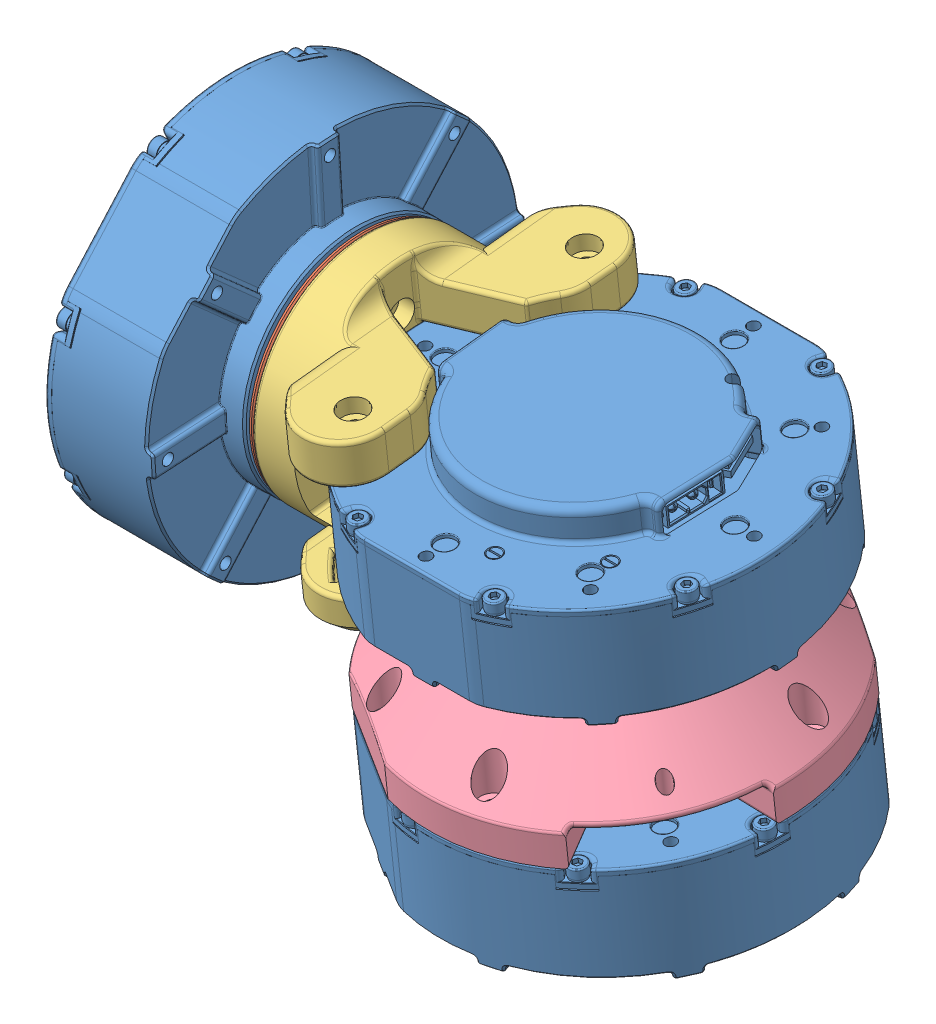
SolidWorks assembly 3自由度单腿-装配体, configuration 默认. Lengths in mm.
Overall size (172.45 137.35 144.34).
11 component instances, 4 part files, 31 mates.
Components (placement in the parent):
- 宇树电机-可转动-1: 宇树电机-可转动 [默认] at (-12.2435 -5.4245 99.9566) size (42.3 98.68 99.96) (flexible)
  - GO-M8010-6电机3D模型-定子-1: GO-M8010-6电机3D模型-定子 [默认] at origin size (42 98.68 99.96)
  - GO-M8010-6电机3D模型-转子-1: GO-M8010-6电机3D模型-转子 [默认] at (105.0963 -198.9147 5.3522) x (1 0 0) z (0 0.306782 -0.95178) size (8.3 59.93 59.79)
- 髋关节连接件 A-1: 髋关节连接件 A [默认] at (101.5018 -193.4249 100.3215) x (0 0.108512 -0.994095) z (0 -0.994095 -0.108512) size (82.01 37.78 59)
- 髋关节连接件 B-1: 髋关节连接件 B [默认] at (160.7523 -214.5992 98.0105) x (0.853082 -0.056619 0.518696) z (0.521777 0.09257 -0.848045) size (93.72 27.46 99.11)
- 宇树电机-可转动-2: 宇树电机-可转动 [默认] at (20.0022 -88.0011 -13.5455) x (0 -0.994095 -0.108512) z (0.664398 0.0811 -0.742965) size (42.3 98.68 99.96) (flexible)
  - GO-M8010-6电机3D模型-定子-1: GO-M8010-6电机3D模型-定子 [默认] at origin size (42 98.68 99.96)
  - GO-M8010-6电机3D模型-转子-1: GO-M8010-6电机3D模型-转子 [默认] at (105.0963 -180.1325 9.4248) x (1 0 0) z (0 -0.999679 -0.025325) size (8.3 59.93 59.79)
- 宇树电机-可转动-3: 宇树电机-可转动 [默认] at (215.7919 -182.3677 282.3599) x (0 -0.994095 -0.108512) z (-0.956751 -0.031567 0.28919) size (42.3 98.68 99.96) (flexible)
  - GO-M8010-6电机3D模型-定子-1: GO-M8010-6电机3D模型-定子 [默认] at origin size (42 98.68 99.96)
  - GO-M8010-6电机3D模型-转子-1: GO-M8010-6电机3D模型-转子 [默认] at (105.0963 -181.6014 10.516) x (1 0 0) z (0 -0.984204 -0.177039) size (8.3 59.93 59.79)
Mates (geometry in assembly coordinates):
- 重合1: coincident anti-aligned: plane of 宇树电机-可转动-1/GO-M8010-6电机3D模型-转子-1 through (101.5018 -165.4622 154.8842) normal (1 0 0); plane of 髋关节连接件 A-1 through (101.5018 -193.4249 100.3215) normal (-1 0 0)
- 同心1: concentric anti-aligned: cylinder of 宇树电机-可转动-1/GO-M8010-6电机3D模型-转子-1 through (97.3518 -203.6201 114.2363) axis (1 0 0) radius 1.65; cylinder of 髋关节连接件 A-1 through (112.5018 -203.6201 114.2363) axis (-1 0 0) radius 2
- 同心2: concentric anti-aligned: cylinder of 宇树电机-可转动-1/GO-M8010-6电机3D模型-转子-1 through (97.3518 -186.4719 116.1081) axis (1 0 0) radius 1.65; cylinder of 髋关节连接件 A-1 through (112.5018 -186.4719 116.1081) axis (-1 0 0) radius 2
- 重合5: coincident anti-aligned: plane of 髋关节连接件 A-1 through (160.7518 -180.5017 101.7321) normal (0 -0.994095 -0.108512); plane of 宇树电机-可转动-2/GO-M8010-6电机3D模型-定子-1 through (75.6761 -181.0443 106.7031) normal (0 0.994095 0.108512)
- 同心6: concentric anti-aligned: cylinder of 髋关节连接件 A-1 through (130.6998 -167.3602 133.3972) axis (0 -0.994095 -0.108512) radius 1.75; cylinder of 宇树电机-可转动-2/GO-M8010-6电机3D模型-定子-1 through (130.6998 -185.9994 131.3626) axis (0 0.994095 0.108512) radius 1.45
- 同心7: concentric anti-aligned: cylinder of 髋关节连接件 A-1 through (130.6998 -160.8381 73.648) axis (0 -0.994095 -0.108512) radius 1.75; cylinder of 宇树电机-可转动-2/GO-M8010-6电机3D模型-定子-1 through (130.6998 -179.4774 71.6134) axis (0 0.994095 0.108512) radius 1.45
- 重合6: coincident anti-aligned: plane of 髋关节连接件 B-1 through (160.7523 -214.5992 98.0105) normal (0 0.994095 0.108512); plane of 宇树电机-可转动-2/GO-M8010-6电机3D模型-转子-1 through (99.4757 -214.8213 100.0447) normal (0 -0.994095 -0.108512)
- 同心8: concentric anti-aligned: cylinder of 髋关节连接件 B-1 through (151.7516 -227.1311 111.4457) axis (0 0.994095 0.108512) radius 2; cylinder of 宇树电机-可转动-2/GO-M8010-6电机3D模型-转子-1 through (151.7516 -212.0705 113.0896) axis (0 -0.994095 -0.108512) radius 1.65
- 同心9: concentric anti-aligned: cylinder of 髋关节连接件 B-1 through (177.9967 -225.5817 97.2513) axis (0 0.994095 0.108512) radius 2; cylinder of 宇树电机-可转动-2/GO-M8010-6电机3D模型-转子-1 through (177.9967 -210.5211 98.8952) axis (0 -0.994095 -0.108512) radius 1.65
- 重合7: coincident anti-aligned: plane of 髋关节连接件 B-1 through (160.7523 -241.8374 95.0373) normal (0 -0.994095 -0.108512); plane of 宇树电机-可转动-3/GO-M8010-6电机3D模型-定子-1 through (235.938 -246.1914 134.9251) normal (0 0.994095 0.108512)
- 同心10: concentric anti-aligned: cylinder of 髋关节连接件 B-1 through (197.0083 -217.0055 120.0551) axis (0 -0.994095 -0.108512) radius 1.75; cylinder of 宇树电机-可转动-3/GO-M8010-6电机3D模型-定子-1 through (197.0083 -246.4805 116.8377) axis (0 0.994095 0.108512) radius 1.45
- 同心11: concentric anti-aligned: cylinder of 髋关节连接件 B-1 through (202.0696 -213.5188 88.1129) axis (0 -0.994095 -0.108512) radius 3.5; cylinder of 宇树电机-可转动-3/GO-M8010-6电机3D模型-定子-1 through (202.0696 -242.9937 84.8955) axis (0 0.994095 0.108512) radius 1.45
- 重合8: coincident anti-aligned: plane of 宇树电机-可转动-3/GO-M8010-6电机3D模型-定子-1 through (179.1136 -261.4195 34.8275) normal (0 -0.994095 -0.108512); plane of 大腿内侧-1 through (282.5576 -1.3738 17.7575) normal (0 0.422474 0.906375)
- 同心13: concentric aligned: cylinder of 宇树电机-可转动-3/GO-M8010-6电机3D模型-定子-1 through (138.5763 -271.7175 128.2466) axis (0 0.994095 0.108512) radius 1.45; cylinder of 大腿内侧-1 through (40.2503 -66.9994 39.5201) axis (0 0.422474 0.906375) radius 2
- 重合12: coincident aligned: plane of 宇树电机-可转动-3/GO-M8010-6电机3D模型-定子-1 through (123.9794 -274.9933 123.3298) normal (-0.521782 -0.09257 0.848041); plane of 大腿内侧-1 through (48.4308 -87.4465 20.7119) normal (-0.588197 -0.733002 0.341662)
- 重合13: coincident anti-aligned: plane of 大腿内侧-1 through (268.7407 -110.0354 145.6506) normal (0 -0.925542 -0.378646); plane of 小腿-1 through (271.1241 -107.7432 140.0476) normal (0 0.925542 0.378646)
- 同心14: concentric anti-aligned: cylinder of 大腿内侧-1 through (268.7407 -110.0354 145.6506) axis (0 0.925542 0.378646) radius 14; cylinder of 小腿-1 through (271.1241 -86.277 148.8296) axis (0 -0.925542 -0.378646) radius 8.2
- 重合16: coincident anti-aligned: plane of 宇树电机-可转动-3/GO-M8010-6电机3D模型-转子-1 through (208.8772 -280.0569 129.0773) normal (0 -0.994095 -0.108512); plane of 宇树电机转凸轮-1 through (65.2487 -36.4602 24.9563) normal (0 0.428336 0.903619)
- 同心16: concentric anti-aligned: cylinder of 宇树电机-可转动-3/GO-M8010-6电机3D模型-转子-1 through (160.7521 -274.6922 91.4507) axis (0 -0.994095 -0.108512) radius 7.5; cylinder of 宇树电机转凸轮-1 through (65.2487 -40.1867 17.0948) axis (0 0.428336 0.903619) radius 10
- 同心17: concentric anti-aligned: cylinder of 宇树电机-可转动-3/GO-M8010-6电机3D模型-转子-1 through (147.8624 -270.5654 80.3693) axis (0 -0.994095 -0.108512) radius 1.65; cylinder of 宇树电机转凸轮-1 through (47.9987 -40.1946 17.0985) axis (0 0.428336 0.903619) radius 1.9
- 重合17: coincident anti-aligned: plane of 宇树电机转凸轮-1 through (65.2487 -40.615 16.1912) normal (0 -0.428336 -0.903619); plane of 传动连杆-1 through (309.7835 -5.4578 -0.4742) normal (0 0.428336 0.903619)
- 同心18: concentric anti-aligned: circle of 宇树电机转凸轮-1; cylinder of 传动连杆-1 through (80.3886 -63.3979 23.1174) axis (0 0.428336 0.903619) radius 2
- 同心19: concentric anti-aligned: cylinder of 小腿-方-1 through (259.5971 -73.794 67.6279) axis (0 -0.925542 -0.378646) radius 2; cylinder of 传动连杆-1 through (296.9235 -28.2534 6.4582) axis (0 0.428336 0.903619) radius 2
- 同心20: concentric anti-aligned: circle of 大腿内侧-1; cylinder of 小腿-方-1 through (285.05 -106.9039 66.6894) axis (0 0.925542 0.378646) radius 5
- 同心21: concentric anti-aligned: cylinder of 小腿-方-1 through (259.5971 -73.794 67.6279) axis (0 -0.925542 -0.378646) radius 2; cylinder of 传动连杆-1 through (296.9235 -28.2534 6.4582) axis (0 0.428336 0.903619) radius 2
- 重合18: coincident anti-aligned: plane of 大腿内侧-1 through (282.5576 -5.176 9.6001) normal (0 -0.422474 -0.906375); plane of 小腿-方-1
- 重合19: coincident anti-aligned: plane of 宇树电机-可转动-3/GO-M8010-6电机3D模型-转子-1 through (208.8772 -280.0569 129.0773) normal (0 -0.994095 -0.108512); plane of 宇树电机转凸轮-3 through (168.5922 -249.6888 34.843) normal (0 0.835228 0.549904)
- 同心22: concentric aligned: cylinder of 宇树电机-可转动-3/GO-M8010-6电机3D模型-定子-1 through (160.7521 -256.1027 93.4799) axis (0 -0.994095 -0.108512) radius 48.25; cylinder of 宇树电机转凸轮-3 through (160.7521 -227.4157 77.9422) axis (0 -0.835228 -0.549904) radius 10
- 同心23: concentric anti-aligned: cylinder of 宇树电机-可转动-3/GO-M8010-6电机3D模型-转子-1 through (147.8624 -270.5654 80.3693) axis (0 -0.994095 -0.108512) radius 1.65; cylinder of 宇树电机转凸轮-3 through (176.3261 -272.34 57.2449) axis (0 0.835228 0.549904) radius 1.65
- 同心24: concentric anti-aligned: cylinder of 传动连杆-3 through (168.5922 -255.6189 30.9386) axis (0 -0.835228 -0.549904) radius 2.05; cylinder of 宇树电机转凸轮-3 through (168.5922 -255.2013 31.2136) axis (0 0.835228 0.549904) radius 2.05
- 重合31: coincident anti-aligned: plane of 传动连杆-3 through (168.5922 -255.6189 30.9386) normal (0 0.835228 0.549904); plane of 宇树电机转凸轮-3 through (168.5922 -255.6189 30.9386) normal (0 -0.835228 -0.549904)
